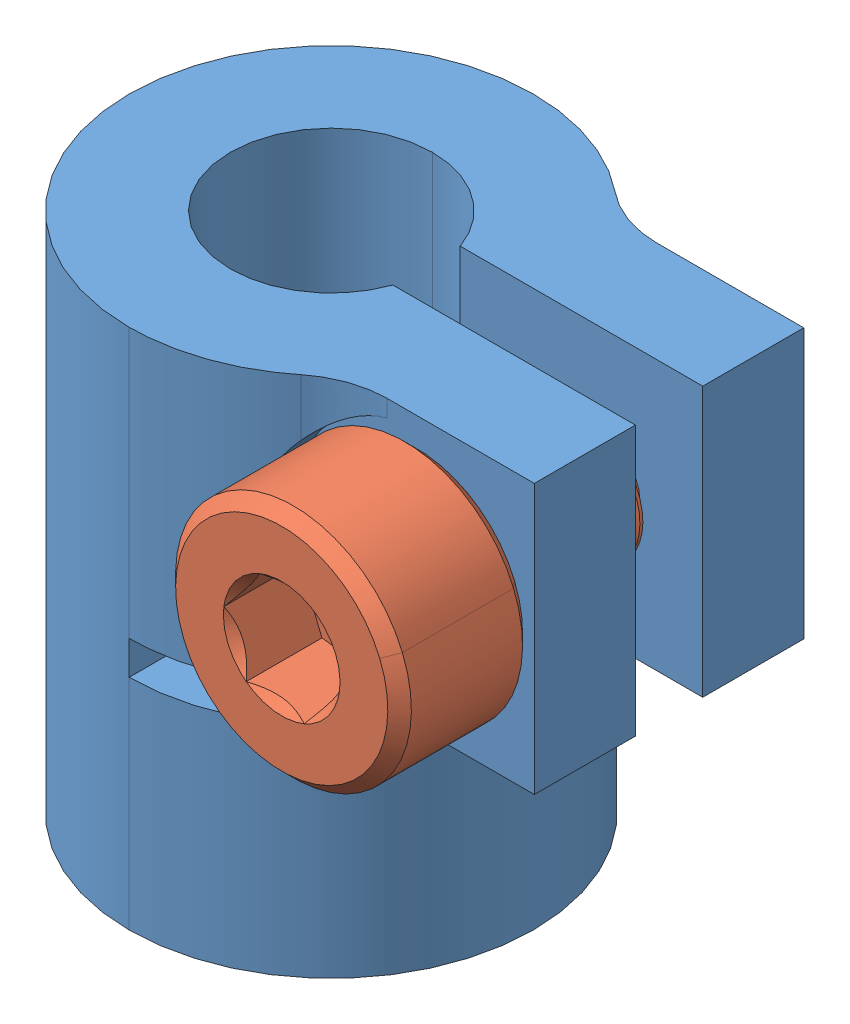
SolidWorks assembly servoCoupler, configuration Default. Lengths in mm.
Overall size (17.1 16.07 14.01).
3 component instances, 2 part files, 0 mates.
Components (placement in the parent):
- 4001-0025-0006 assembly.STEP-1: 4001-0025-0006 assembly.STEP [Default] at origin size (17.1 16.07 14.01)
  - 4001-0025-0006.STEP-1: 4001-0025-0006.STEP [Default] at (-51.8616 6.0214 22.0431) size (16.03 15.5 12)
  - 2800-0004-0008_90128A207.STEP-1: 2800-0004-0008_90128A207.STEP [Default] at (-45.3332 10.0214 18.0431) x (-0.923728 -0.383049 0) z (0 0 -1) size (7 7 12.01)
